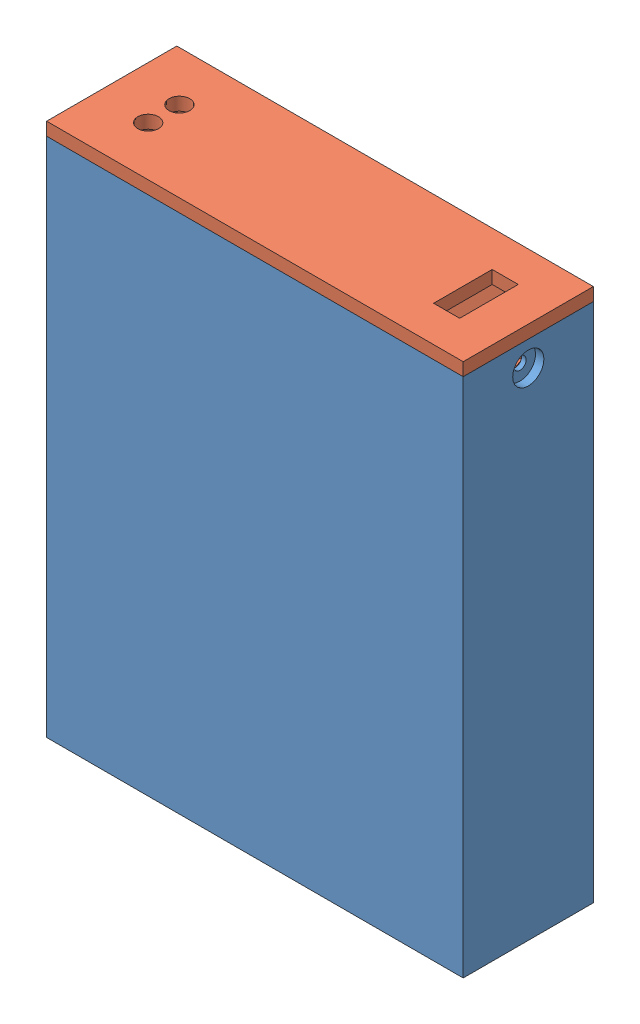
SolidWorks assembly 18650-holder-2, configuration Default. Lengths in mm.
Overall size (101.6 130.18 31.75).
2 component instances, 2 part files, 3 mates.
Components (placement in the parent):
- 18650-holder-1-1: 18650-holder-1 [Default] at (-5.7912 -75.1473 10.9689) size (101.6 127 31.75)
- Part4^18650-holder-2-1: Part4^18650-holder-2 [Default] at (-5.7912 0 -4.9061) size (101.6 15.88 31.75) (virtual)
Mates (geometry in assembly coordinates):
- Width1: width: plane of 18650-holder-1-1 through (41.8338 -173.7258 -1.7311) normal (0 0 1); plane of 18650-holder-1-1 through (-53.4162 -173.7258 23.6689) normal (0 0 -1); plane of Part4^18650-holder-2-1 through (-52.6225 39.1527 -0.9373) normal (0 0 -1); plane of Part4^18650-holder-2-1 through (41.04 39.1527 22.8752) normal (0 0 1)
- Width2: width: plane of 18650-holder-1-1 through (41.8338 -173.7258 23.6689) normal (-1 0 0); plane of 18650-holder-1-1 through (-53.4162 -173.7258 -1.7311) normal (1 0 0); plane of Part4^18650-holder-2-1 through (41.04 39.1527 -0.9373) normal (1 0 0); plane of Part4^18650-holder-2-1 through (-52.6225 39.1527 22.8752) normal (-1 0 0)
- Coincident2: coincident: plane of 18650-holder-1-1 through (-5.7912 51.8527 10.9689) normal (0 1 0); plane of Part4^18650-holder-2-1 through (-5.7912 51.8527 -4.9061) normal (0 -1 0)
